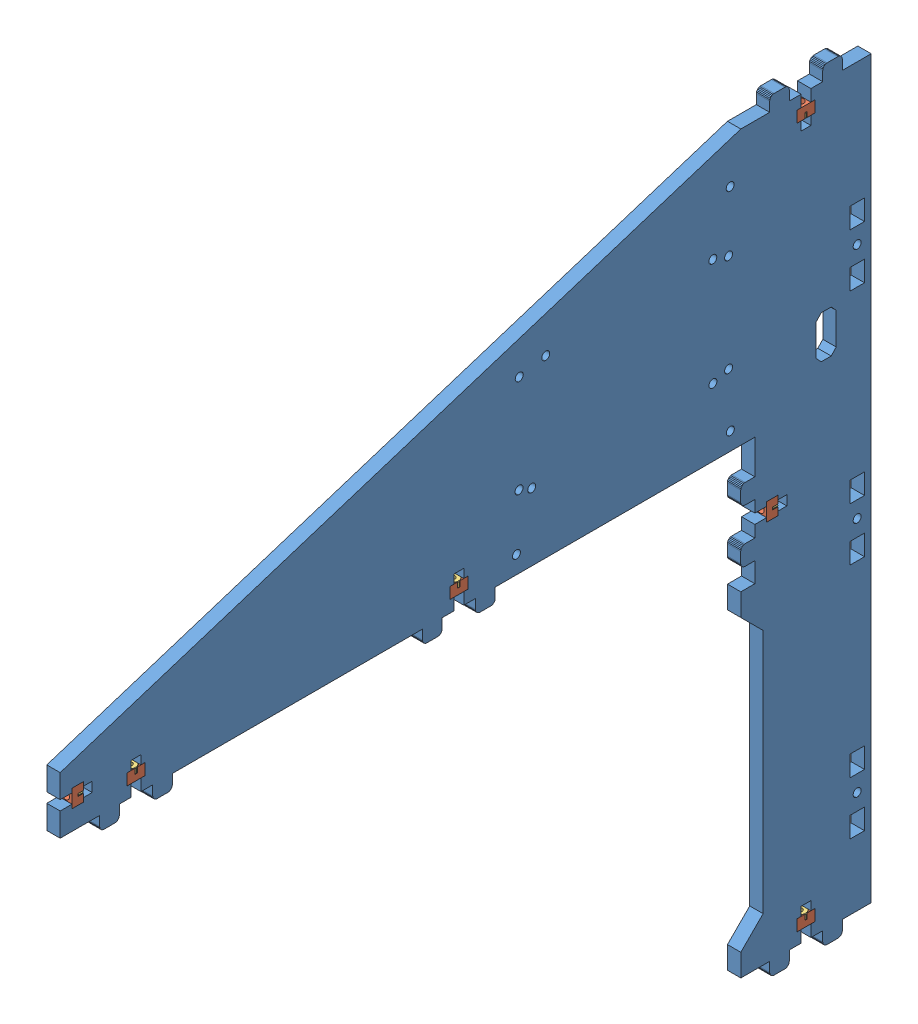
SolidWorks assembly Assembly Left Brace, configuration Valor predeterminado. Lengths in mm.
Overall size (7.94 342.6 363.9).
19 component instances, 3 part files, 21 mates.
Components (placement in the parent):
- Brace-1: Brace [Valor predeterminado] at (0 192.984 -281.4657) x (0 -1 0) z (-1 0 0) size (342.6 363.9 6)
- Assembly m3-nut-adapter + Nut DIN 934 - M3-1: Assembly m3-nut-adapter + Nut DIN 934 - M3 [Valor predeterminado] at (-3 117.6 -228.1836) x (0 0 1) z (0 -1 0) size (8.25 7.94 5.1)
  - m3-nut-adapter-1: m3-nut-adapter [Valor predeterminado] at origin size (8 6 5.1)
  - Nut DIN 934 - M3-1: Nut DIN 934 - M3 [Valor predeterminado] at (0 0 3.9) x (0 0 1) z (-0.866025 -0.5 0) size (2.4 5.5 6.35)
- Assembly m3-nut-adapter + Nut DIN 934 - M3-2: Assembly m3-nut-adapter + Nut DIN 934 - M3 [Valor predeterminado] at (-3 5.3 -72.4337) x (0 0 1) z (0 1 0) size (8.25 7.94 5.1)
  - m3-nut-adapter-1: m3-nut-adapter [Valor predeterminado] at origin size (8 6 5.1)
  - Nut DIN 934 - M3-1: Nut DIN 934 - M3 [Valor predeterminado] at (0 0 3.9) x (0 0 1) z (-0.866025 -0.5 0) size (2.4 5.5 6.35)
- Assembly m3-nut-adapter + Nut DIN 934 - M3-3: Assembly m3-nut-adapter + Nut DIN 934 - M3 [Valor predeterminado] at (-3 5.3 72.4337) x (0 0 -1) z (0 1 0) size (8.25 7.94 5.1)
  - m3-nut-adapter-1: m3-nut-adapter [Valor predeterminado] at origin size (8 6 5.1)
  - Nut DIN 934 - M3-1: Nut DIN 934 - M3 [Valor predeterminado] at (0 0 3.9) x (0 0 1) z (-0.866025 -0.5 0) size (2.4 5.5 6.35)
- Assembly m3-nut-adapter + Nut DIN 934 - M3-4: Assembly m3-nut-adapter + Nut DIN 934 - M3 [Valor predeterminado] at (-3 -31.7 -210.5336) x (0 -1 0) z (0 0 -1) size (8.25 7.94 5.1)
  - m3-nut-adapter-1: m3-nut-adapter [Valor predeterminado] at origin size (8 6 5.1)
  - Nut DIN 934 - M3-1: Nut DIN 934 - M3 [Valor predeterminado] at (0 0 3.9) x (0 0 1) z (-0.866025 -0.5 0) size (2.4 5.5 6.35)
- Assembly m3-nut-adapter + Nut DIN 934 - M3-5: Assembly m3-nut-adapter + Nut DIN 934 - M3 [Valor predeterminado] at (-3 -201.6999 -228.1836) x (0 0 1) z (0 1 0) size (8.25 7.94 5.1)
  - m3-nut-adapter-1: m3-nut-adapter [Valor predeterminado] at origin size (8 6 5.1)
  - Nut DIN 934 - M3-1: Nut DIN 934 - M3 [Valor predeterminado] at (0 0 3.9) x (0 0 1) z (-0.866025 -0.5 0) size (2.4 5.5 6.35)
- Assembly m3-nut-adapter + Nut DIN 934 - M3-6: Assembly m3-nut-adapter + Nut DIN 934 - M3 [Valor predeterminado] at (-3 12.8 101.1663) x (0 1 0) z (0 0 -1) size (8.25 7.94 5.1)
  - m3-nut-adapter-1: m3-nut-adapter [Valor predeterminado] at origin size (8 6 5.1)
  - Nut DIN 934 - M3-1: Nut DIN 934 - M3 [Valor predeterminado] at (0 0 3.9) x (0 0 1) z (-0.866025 -0.5 0) size (2.4 5.5 6.35)
Mates (geometry in assembly coordinates):
- Coincidente1: coincident: plane of ? through (-6 192.984 -24.0321) normal (-1 0 0); plane of ? through (-6 112.5 25.25) normal (-1 0 0)
- Coincidente2: coincident: plane of ? through (-6 117.6 25.25) normal (0 0 1); plane of ? through (-6 112.5 25.25) normal (0 0 -1)
- Coincidente3: coincident: plane of ? through (-6 117.6 27.05) normal (0 -1 0); plane of ? through (-3 117.6 29.25) normal (0 1 0)
- Coincidente4: coincident: plane of ? through (-6 192.984 -24.0321) normal (-1 0 0); plane of ? through (-6 10.4 333.8673) normal (-1 0 0)
- Coincidente5: coincident: plane of ? through (-6 10.4 325.8673) normal (0 0 1); plane of ? through (-6 10.4 325.8673) normal (0 0 -1)
- Coincidente6: coincident: plane of ? through (-6 5.3 325.8673) normal (0 1 0); plane of ? through (-3 5.3 329.8673) normal (0 -1 0)
- Coincidente7: coincident: plane of ? through (-6 192.984 -24.0321) normal (-1 0 0); plane of ? through (-6 10.4 180.9999) normal (-1 0 0)
- Coincidente8: coincident: plane of ? through (-6 10.4 180.9999) normal (0 0 1); plane of ? through (0 10.4 180.9999) normal (0 0 -1)
- Coincidente9: coincident: plane of ? through (-6 5.3 180.9999) normal (0 1 0); plane of ? through (-3 5.3 184.9999) normal (0 -1 0)
- Coincidente10: coincident: plane of ? through (-6 192.984 -24.0321) normal (-1 0 0); plane of ? through (-6 -27.7 41.8) normal (-1 0 0)
- Coincidente11: coincident: plane of ? through (-6 -35.7 46.9) normal (0 1 0); plane of ? through (-6 -35.7 41.8) normal (0 -1 0)
- Coincidente12: coincident: plane of ? through (-6 -33.9 46.9) normal (0 0 -1); plane of ? through (-3 -31.7 46.9) normal (0 0 1)
- Coincidente13: coincident: plane of ? through (-6 192.984 -24.0321) normal (-1 0 0); plane of ? through (-6 -196.5999 25.25) normal (-1 0 0)
- Coincidente14: coincident: plane of ? through (-6 -196.5999 25.25) normal (0 0 1); plane of ? through (0 -196.5999 25.25) normal (0 0 -1)
- Coincidente15: coincident: plane of ? through (-6 -201.6999 25.25) normal (0 1 0); plane of ? through (-3 -201.6999 29.25) normal (0 -1 0)
- Coincidente16: coincident: plane of ? through (-6 192.984 -24.0321) normal (-1 0 0); plane of ? through (-6 8.8 353.4999) normal (-1 0 0)
- Coincidente17: coincident: plane of ? through (-6 8.8 358.5999) normal (0 1 0); plane of ? through (0 8.8 353.4999) normal (0 -1 0)
- Coincidente18: coincident: plane of ? through (-6 10.6 358.5999) normal (0 0 -1); plane of ? through (-3 12.8 358.5999) normal (0 0 1)
- Coincidente19: coincident: plane of ? through (-6 0 52.2) normal (0 -1 0)
- Coincidente21: coincident: plane of ? through (0 192.984 -24.0321) normal (1 0 0)
- Simétrico1: symmetric: plane of assembly; plane of assembly; plane of Brace-1 through (-6 0 88.7336) normal (0 0 1); plane of Brace-1 through (-6 -4.35 -88.7336) normal (0 0 -1); plane of assembly
